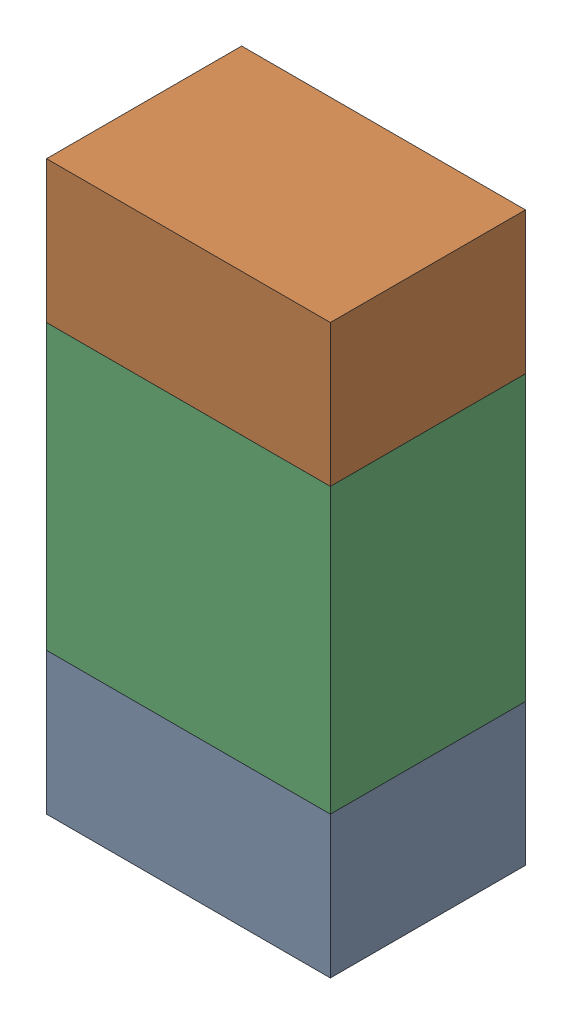
SolidWorks assembly R49, configuration ﾃﾞﾌｫﾙﾄ. Lengths in mm.
Overall size (0.8 1.6 0.55).
6 component instances, 2 part files, 0 mates.
Components (placement in the parent):
- 689261784-1: 689261784 [ﾃﾞﾌｫﾙﾄ] at (69.0001 35.1501 -1.7503) size (0.8 0.4 0.55)
  - Extruded_34-1: Extruded_34 [ﾃﾞﾌｫﾙﾄ] at origin size (0.8 0.4 0.55)
- 689261784-2: 689261784 [ﾃﾞﾌｫﾙﾄ] at (69.0001 36.3501 -1.7503) size (0.8 0.4 0.55)
  - Extruded_34-1: Extruded_34 [ﾃﾞﾌｫﾙﾄ] at origin size (0.8 0.4 0.55)
- 689261648-1: 689261648 [ﾃﾞﾌｫﾙﾄ] at (69.0001 35.75 -1.7503) size (0.8 0.8 0.55)
  - Extruded_33-1: Extruded_33 [ﾃﾞﾌｫﾙﾄ] at origin size (0.8 0.8 0.55)
